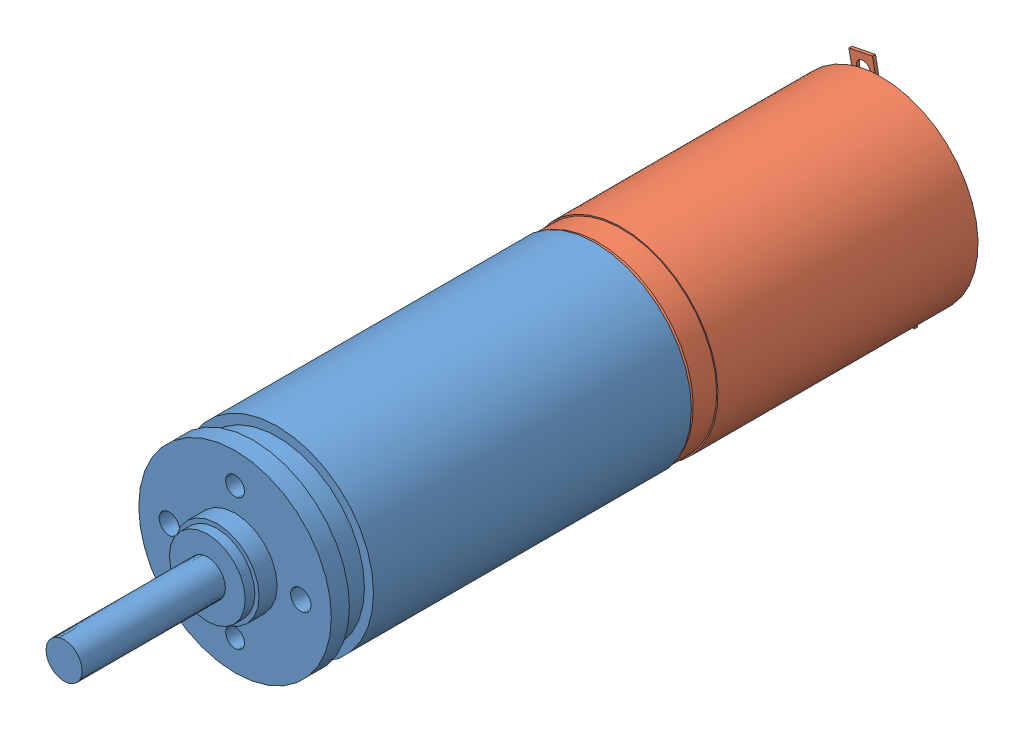
SolidWorks assembly Assem2, configuration Default. Lengths in mm.
Overall size (19.2 20.94 68.9).
2 component instances, 2 part files, 2 mates.
Components (placement in the parent):
- 15_5 3stages-1: 15_5 3stages [Default] at (5.9744 18.3704 42.539) size (16 16 44.1)
- 1624S-1: 1624S [Default] at (5.9744 18.3704 -12.161) x (0.192236 -0.981349 0) z (0 0 1) size (18.2 16 32.9)
Mates (geometry in assembly coordinates):
- Coincident1: coincident: circle of 15_5 3stages-1; plane of 1624S-1 through (32.6893 8.562 12.639) normal (0 0 1)
- Concentric3: concentric aligned: circle of 15_5 3stages-1; circle of 1624S-1
